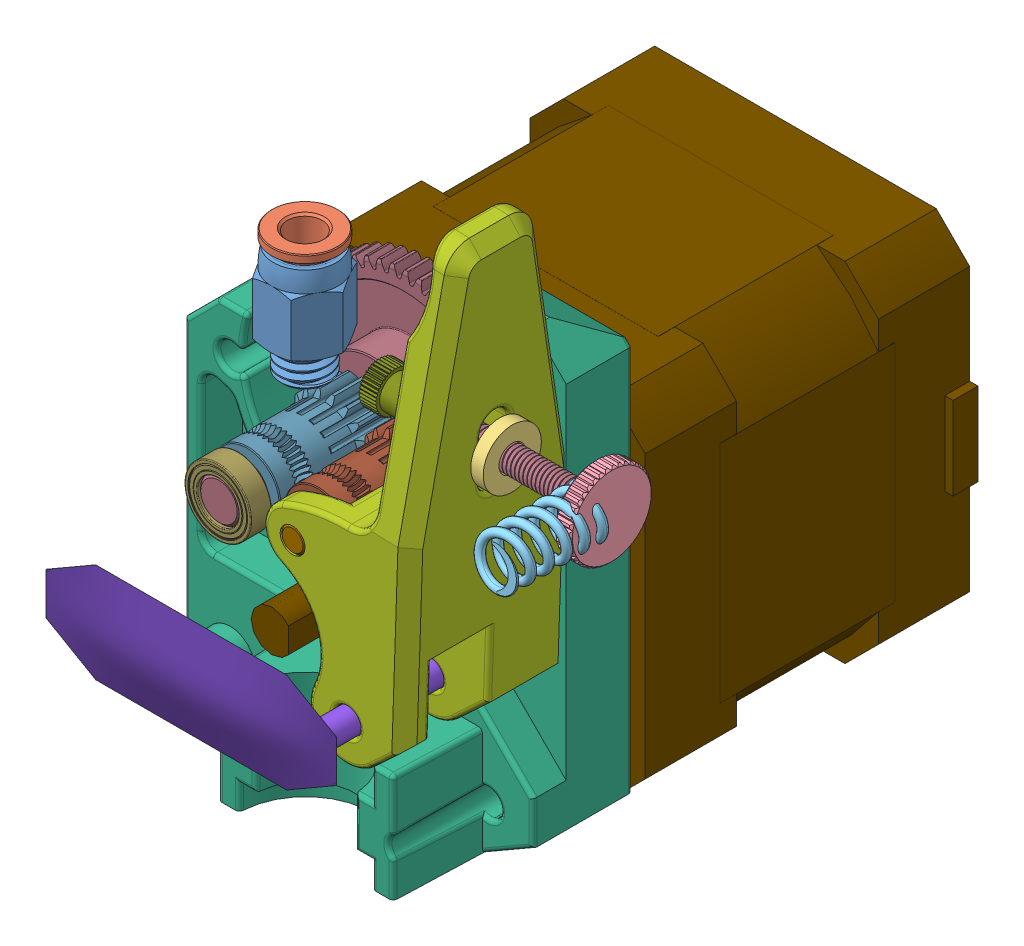
SolidWorks assembly BMG Extruder, configuration Default. Lengths in mm.
Overall size (59.13 72.87 75.12).
27 component instances, 20 part files, 3 mates.
Components (placement in the parent):
- BMG Extruder(2)^BMG Extruder-1: BMG Extruder(2)^BMG Extruder [Default] at origin size (59.12 72.86 40.49) (virtual)
  - PC4-M6C complete^BMG Extruder(2)_BMG Extruder-1: PC4-M6C complete^BMG Extruder(2)_BMG Extruder [Default] at origin size (9.24 15.06 8) (virtual)
    - body^PC4-M6C complete_BMG Extruder(2)_BMG Extruder-1: body^PC4-M6C complete_BMG Extruder(2)_BMG Extruder [Default] at (25 54 -10.5) size (9.24 13.33 8) (virtual)
    - release sleeve^PC4-M6C complete_BMG Extruder(2)_BMG Extruder-1: release sleeve^PC4-M6C complete_BMG Extruder(2)_BMG Extruder [Default] at (25 54 -10.5) size (8 6.5 8) (virtual)
  - thumbscrew assembly^BMG Extruder(2)_BMG Extruder-1: thumbscrew assembly^BMG Extruder(2)_BMG Extruder [Default] at origin size (23.17 9.99 18.21) (virtual)
    - M3 washer - nylon^thumbscrew assembly_BMG Extruder(2)_BMG Extruder-1: M3 washer - nylon^thumbscrew assembly_BMG Extruder(2)_BMG Extruder [Default] at (46.0002 49.5 -14.5) x (0 0.555211 -0.83171) z (-1 0 0) size (7 7 1.5) (virtual)
    - Thumbscrew^thumbscrew assembly_BMG Extruder(2)_BMG Extruder-1: Thumbscrew^thumbscrew assembly_BMG Extruder(2)_BMG Extruder [Default] at (56 49.5 -14.5) x (0 1 0) z (0 0 -1) size (9.99 22.05 9.99) (virtual)
    - Spring^thumbscrew assembly_BMG Extruder(2)_BMG Extruder-1: Spring^thumbscrew assembly_BMG Extruder(2)_BMG Extruder [Default] at (56 49.5 -14.5) x (0 1 0) z (0 0 1) size (6.26 6.24 13.57) (virtual)
  - BMG Back^BMG Extruder(2)_BMG Extruder-1: BMG Back^BMG Extruder(2)_BMG Extruder [Default] at (0 0 -33) size (42 54 22.4) (virtual)
  - BMG Front^BMG Extruder(2)_BMG Extruder-1: BMG Front^BMG Extruder(2)_BMG Extruder [Default] x (-1 0 0) z (0 0 -1) size (42 54 21.01) (hidden, virtual)
  - BMG Arm^BMG Extruder(2)_BMG Extruder-1: BMG Arm^BMG Extruder(2)_BMG Extruder [Default] at (42.8457 17.2686 -24.5) x (0 0 1) z (-0.999441 0.033421 0) size (20.01 55.04 17.5) (virtual)
  - M3x30 shaft^BMG Extruder(2)_BMG Extruder-1: M3x30 shaft^BMG Extruder(2)_BMG Extruder [Default] at (36 22 -16.3) size (3 3 30) (virtual)
  - M3x20 shaft^BMG Extruder(2)_BMG Extruder-1: M3x20 shaft^BMG Extruder(2)_BMG Extruder [Default] at (29.5219 37.7253 -14.5) x (0.999441 -0.033421 0) z (0 0 1) size (3 3 20) (virtual)
  - 3x5x7 needle bearing^BMG Extruder(2)_BMG Extruder-1: 3x5x7 needle bearing^BMG Extruder(2)_BMG Extruder [Default] at (29.5219 37.7253 -11) x (1 -0.00091 0) z (0 0 1) size (5 5 7) (virtual)
  - 3x5x7 needle bearing^BMG Extruder(2)_BMG Extruder-2: 3x5x7 needle bearing^BMG Extruder(2)_BMG Extruder [Default] at (29.5219 37.7253 -18) x (1 -0.00091 0) z (0 0 1) size (5 5 7) (virtual)
  - BMG filament gear - driven^BMG Extruder(2)_BMG Extruder-1: BMG filament gear - driven^BMG Extruder(2)_BMG Extruder [Default] at (21.0238 37.5488 -21.5) x (0.999784 0.020767 0) z (0.020767 -0.999784 0) size (9.5 14.01 9.51) (virtual)
  - 5x8x2.5 MR58(zz) ball bearing^BMG Extruder(2)_BMG Extruder-1: 5x8x2.5 MR58(zz) ball bearing^BMG Extruder(2)_BMG Extruder [Default] at (21 37.7 -5.25) x (0 0 1) z (-1 0 0) size (2.5 8 8) (virtual)
  - 5x8x2.5 MR58(zz) ball bearing^BMG Extruder(2)_BMG Extruder-2: 5x8x2.5 MR58(zz) ball bearing^BMG Extruder(2)_BMG Extruder [Default] at (21 37.7 -31.15) x (0 0 1) z (-1 0 0) size (2.5 8 8) (virtual)
  - BMG shaft^BMG Extruder(2)_BMG Extruder-1: BMG shaft^BMG Extruder(2)_BMG Extruder [Default] at (21 37.7 -29.4) x (0.999875 -0.015798 0) z (-0.015798 -0.999875 0) size (25.97 28.25 26) (virtual)
  - BMG filament gear - driver^BMG Extruder(2)_BMG Extruder-1: BMG filament gear - driver^BMG Extruder(2)_BMG Extruder [Default] at (12.5011 37.8343 -21.5) x (0.999875 -0.015798 0) z (-0.015798 -0.999875 0) size (9.5 14.01 9.51) (virtual)
  - BMG motor gear^BMG Extruder(2)_BMG Extruder-1: BMG motor gear^BMG Extruder(2)_BMG Extruder [Default] at (21.0565 21.0565 -34.5) x (-0.13775 -0.990467 0) z (-0.990467 0.13775 0) size (9.95 13 10.56) (virtual)
  - M3x8x5 threaded insert^BMG Extruder(2)_BMG Extruder-1: M3x8x5 threaded insert^BMG Extruder(2)_BMG Extruder [Default] at (34 49.5 -14.5) x (0 -1 0) z (0 0 1) size (4.99 8.1 4.99) (virtual)
  - M3x35 cap head screw (partial thread)^BMG Extruder(2)_BMG Extruder-1: M3x35 cap head screw (partial thread)^BMG Extruder(2)_BMG Extruder [Default] at (5.5 5.5 -4) x (1 0 0) z (0 -1 0) size (5.5 38 5.5) (hidden, virtual)
  - M3x35 cap head screw (partial thread)^BMG Extruder(2)_BMG Extruder-2: M3x35 cap head screw (partial thread)^BMG Extruder(2)_BMG Extruder [Default] at (5.5 36.5 -4) x (1 0 0) z (0 -1 0) size (5.5 38 5.5) (hidden, virtual)
  - M3x35 cap head screw (partial thread)^BMG Extruder(2)_BMG Extruder-3: M3x35 cap head screw (partial thread)^BMG Extruder(2)_BMG Extruder [Default] at (36.5 5.5 -4) x (1 0 0) z (0 -1 0) size (5.5 38 5.5) (hidden, virtual)
  - Decal^BMG Extruder(2)_BMG Extruder-1: Decal^BMG Extruder(2)_BMG Extruder [Default] at (19.6812 14.9904 -0.6) size (37.89 14.89 3.73) (virtual)
- STEPPER-1: STEPPER [Default] at (21 21 -73.6349) x (0 -1 0) z (0 0 1) size (42.02 53.01 63.12)
Mates (geometry in assembly coordinates):
- Concentric1: concentric aligned: cylinder of BMG Extruder(2)^BMG Extruder-1/BMG Back^BMG Extruder(2)_BMG Extruder-1 through (21 21 -33) axis (0 0 1) radius 11.1; cylinder of STEPPER-1 through (21 21 -34.5189) axis (0 0 1) radius 11
- Concentric2: concentric aligned: cylinder of BMG Extruder(2)^BMG Extruder-1/BMG Back^BMG Extruder(2)_BMG Extruder-1 through (5.5 5.5 -33) axis (0 0 1) radius 1.6; cylinder of STEPPER-1 through (5.5 5.5 -39.5189) axis (0 0 1) radius 1.2295
- Distance1: distance = 1.5189 mm anti-aligned: plane of BMG Extruder(2)^BMG Extruder-1/BMG Back^BMG Extruder(2)_BMG Extruder-1 through (21 27 -33) normal (0 0 -1); plane of STEPPER-1 through (21 21 -34.5189) normal (0 0 1)
